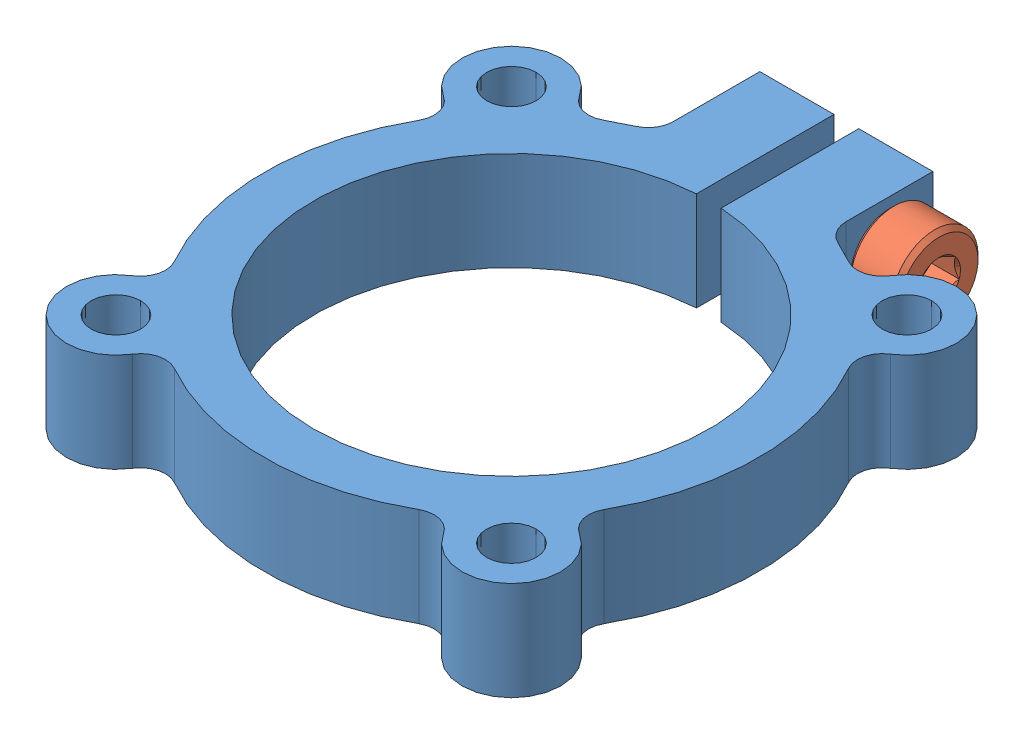
SolidWorks assembly 32mm Clamping Hub 1305-0032-0032, configuration Default. Lengths in mm.
Overall size (40 8.06 47.63).
2 component instances, 2 part files, 0 mates.
Components (placement in the parent):
- 1305-0032-0032.STEP-1: 1305-0032-0032.STEP [Default] at (-26.7164 16.1346 3.9687) size (40 8 47.1)
- 2800-0004-0014_90128A207.STEP-1: 2800-0004-0014_90128A207.STEP [Default] at (-33.7164 20.1346 -19.6313) x (0 -0.166011 0.986124) z (-1 0 0) size (7 7 18.01)
